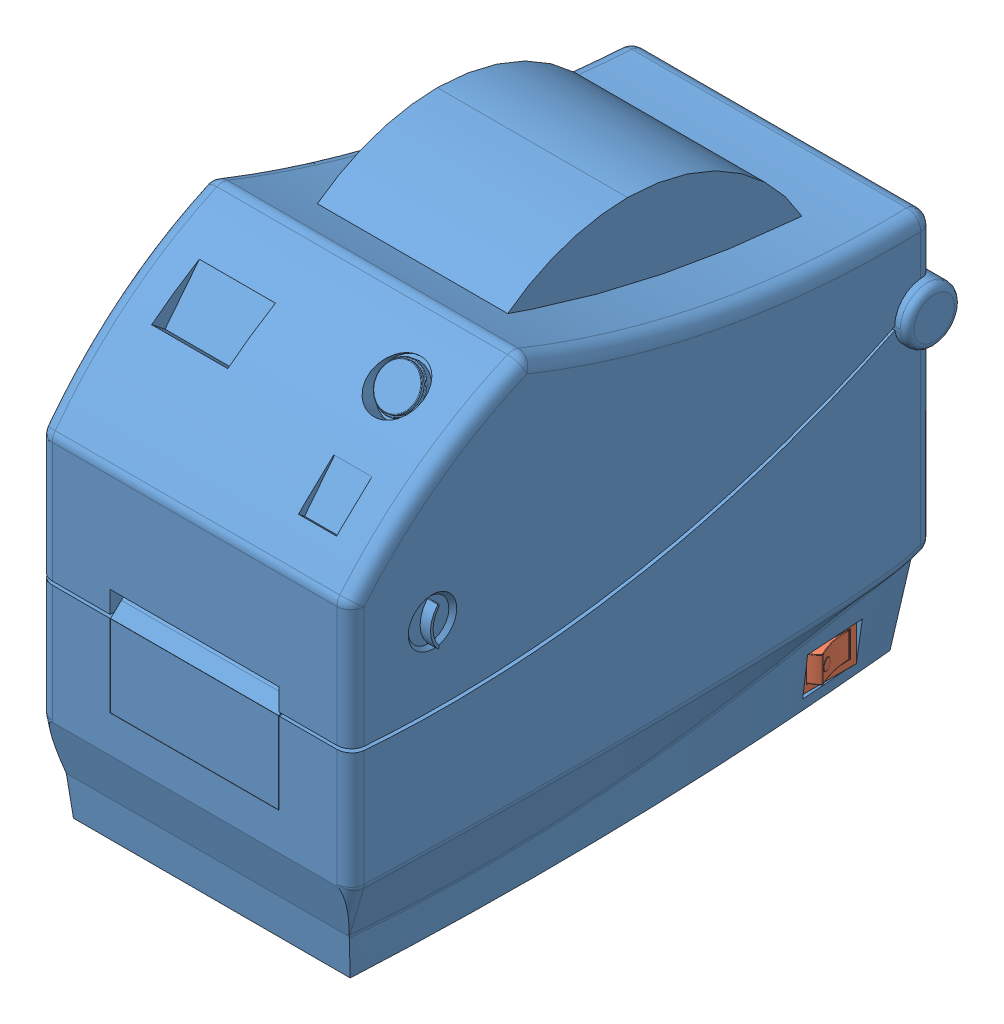
SolidWorks assembly TLP 2824 Plus, configuration Default. Lengths in mm.
Overall size (156.77 202.08 222.53).
4 component instances, 4 part files, 9 mates.
Components (placement in the parent):
- Printer-1: Printer [Default] at (64.5656 19.3731 170.4029) size (156.77 202.08 222.53)
- Rocker Switch-1: Rocker Switch [Default] at (110.6573 31.0707 93.7809) x (0 0 1) z (1 0 0) size (21.4 15.04 26.71)
- VGA Hembra-1: VGA Hembra [Default] at (69.6264 31.9525 70.2765) x (-1 0 0) z (0 0.994651 -0.103291) size (30.9 15.1 12.4)
- USB B Hembra-1: USB B Hembra [Default] at (42.4239 27.8305 84.8) x (-1 0 0) z (0 -0.103291 -0.994651) size (14.95 14.22 16.5)
Mates (geometry in assembly coordinates):
- Concentric2: concentric anti-aligned: cylinder of Printer-1 through (97.7806 31.0707 86.2809) axis (1 0 0) radius 0.125; cylinder of Rocker Switch-1 through (89.2073 31.0707 86.2809) axis (-1 0 0) radius 0.125
- Concentric3: concentric anti-aligned: cylinder of Printer-1 through (97.7806 31.0707 101.2809) axis (1 0 0) radius 0.125; cylinder of Rocker Switch-1 through (89.2073 31.0707 101.2809) axis (-1 0 0) radius 0.125
- Distance2: distance = 0 mm anti-aligned: plane of Rocker Switch-1 through (97.9076 31.0707 100.9936) normal (-1 0 0); plane of Printer-1 through (97.9076 19.3731 170.4029) normal (1 0 0)
- Distance3: distance = 0 mm anti-aligned: plane of Printer-1 through (84.5764 27.1609 79.3198) normal (0 -0.103291 -0.994651); plane of VGA Hembra-1 through (67.0764 34.0986 78.5994) normal (0 0.103291 0.994651)
- Distance4: distance = 0 mm anti-aligned: plane of VGA Hembra-1 through (85.0764 38.1709 70.1334) normal (0 0.994651 -0.103291); plane of Printer-1 through (84.5764 38.9973 78.0906) normal (0 -0.994651 0.103291)
- Distance5: distance = 0 mm anti-aligned: plane of VGA Hembra-1 through (85.0764 25.8373 71.4142) normal (1 0 0); plane of Printer-1 through (85.0764 38.4999 78.1423) normal (-1 0 0)
- Distance6: distance = 0 mm anti-aligned: plane of USB B Hembra-1 through (29.9568 36.9867 67.4428) normal (0 0.994651 -0.103291); plane of Printer-1 through (48.4239 38.9005 85.8723) normal (0 -0.994651 0.103291)
- Distance7: distance = 0 mm anti-aligned: plane of Printer-1 through (36.4239 38.9005 85.8723) normal (1 0 0); plane of USB B Hembra-1 through (36.4239 35.216 76.8791) normal (-1 0 0)
- Distance8: distance = 0 mm anti-aligned: plane of USB B Hembra-1 through (29.9568 56.9248 84.0005) normal (0 0.103291 0.994651); plane of Printer-1 through (64.5656 10.8969 88.7803) normal (0 -0.103291 -0.994651)
